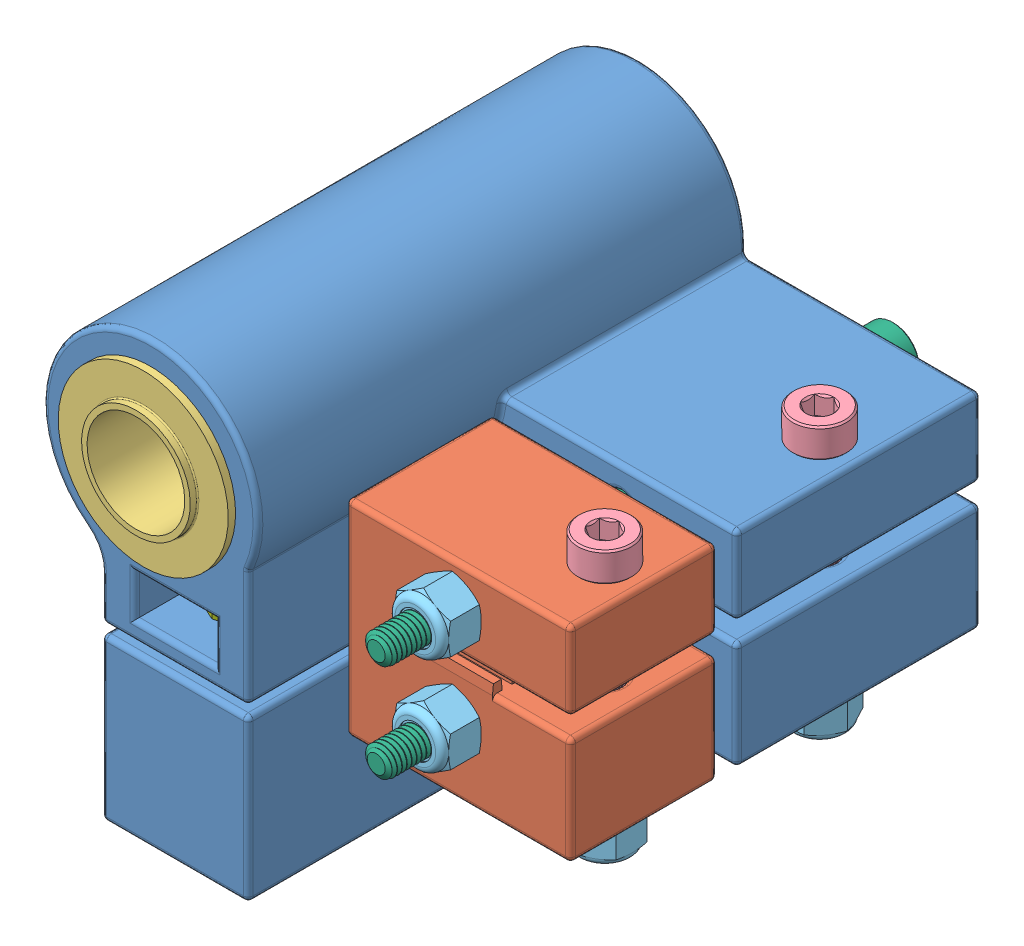
SolidWorks assembly XY_Axis_Belt_Tensioner_B, configuration Default. Lengths in mm.
Overall size (46.09 45 54.64).
14 component instances, 8 part files, 28 mates.
Components (placement in the parent):
- XY Axis Belt Tensioner B-1: XY Axis Belt Tensioner B [Default] at origin size (46 45 50)
- XY Axis Belt Tensioner Block B-1: XY Axis Belt Tensioner Block B [Default] at (0 1 -55.5) size (23 21 15.06)
- a_7z41mpsb10m-1: a_7z41mpsb10m [Default] at (5 34 -24.25) x (1 0 0) z (0 1 0) size (17.4 11.55 17.4)
- a_7z41mpsb10m-2: a_7z41mpsb10m [Default] at (5 34 -75.75) x (1 0 0) z (0 -1 0) size (17.4 11.55 17.4)
- 3mmX25mm_Sockethead(McMaster_91290A125)-1: 3mmX25mm_Sockethead(McMaster_91290A125) [91290A125] at (36 8 -40.5) x (1 0 0) z (0 -1 0) size (5.5 5.5 28.26)
- 3mmX25mm_Sockethead(McMaster_91290A125)-2: 3mmX25mm_Sockethead(McMaster_91290A125) [91290A125] at (36 8 -62.5) x (1 0 0) z (0 -1 0) size (5.5 5.5 28.26)
- 3mm_Hex_Nylock_Nut(McMaster_90576A102)-1: 3mm_Hex_Nylock_Nut(McMaster_90576A102) [90576A102] at (36 12 -40.5) x (1 0 0) z (0 0 -1) size (5.5 4.1 6.35)
- 3mm_Hex_Nylock_Nut(McMaster_90576A102)-2: 3mm_Hex_Nylock_Nut(McMaster_90576A102) [90576A102] at (36 12 -62.5) x (0.810201 0 0.586153) z (0.586153 0 -0.810201) size (5.5 4.1 6.35)
- 3mm_Hex_Nylock_Nut(McMaster_90576A102)-3: 3mm_Hex_Nylock_Nut(McMaster_90576A102) [90576A102] at (28.1 19 -33) x (1 0 0) z (0 -1 0) size (5.5 4.1 6.35)
- 3mm_Hex_Nylock_Nut(McMaster_90576A102)-4: 3mm_Hex_Nylock_Nut(McMaster_90576A102) [90576A102] at (28.1 29 -33) x (1 0 0) z (0 -1 0) size (5.5 4.1 6.35)
- 3mmX50mm_Sockethead(McMaster_91290A137)-1: 3mmX50mm_Sockethead(McMaster_91290A137) [91290A137] at (28.1 29 -25) size (5.5 5.5 53.26)
- 3mmX50mm_Sockethead(McMaster_91290A137)-2: 3mmX50mm_Sockethead(McMaster_91290A137) [91290A137] at (28.1 19 -25) size (5.5 5.5 53.26)
- 5mm_Hex_Nut(McMaster_90591A146)-1: 5mm_Hex_Nut(McMaster_90591A146) [90591A146] at (7.5 21.375 -33.4) x (0.5 0 -0.866025) z (0.866025 0 0.5) size (8 4.31 9.24)
- 5mmX16mm_Buttonhead(McMaster_91239A232)-1: 5mmX16mm_Buttonhead(McMaster_91239A232) [91239A232] at (7.5 3.25 -33.4) x (1 0 0) z (0 -1 0) size (9.5 9.5 19.24)
Mates (geometry in assembly coordinates):
- Concentric1: concentric anti-aligned: cylinder of XY Axis Belt Tensioner B-1 through (5 34 -36) axis (0 0 1) radius 7.95; circle of a_7z41mpsb10m-1
- Coincident1: coincident anti-aligned: plane of XY Axis Belt Tensioner B-1 through (-4 22 -25) normal (0 0 1); plane of a_7z41mpsb10m-1 through (5 34 -25) normal (0 0 -1)
- Concentric2: concentric anti-aligned: cylinder of XY Axis Belt Tensioner B-1 through (5 34 -64) axis (0 0 -1) radius 7.95; circle of a_7z41mpsb10m-2
- Coincident2: coincident anti-aligned: plane of XY Axis Belt Tensioner B-1 through (-4 22 -75) normal (0 0 -1); plane of a_7z41mpsb10m-2 through (5 34 -75) normal (0 0 1)
- Concentric7: concentric aligned: cylinder of XY Axis Belt Tensioner B-1 through (28.1 29 -75) axis (0 0 1) radius 1.6; cylinder of XY Axis Belt Tensioner Block B-1 through (28.1 29 -48) axis (0 0 1) radius 1.6
- Concentric8: concentric aligned: cylinder of XY Axis Belt Tensioner B-1 through (28.1 19 -75) axis (0 0 1) radius 1.6; cylinder of XY Axis Belt Tensioner Block B-1 through (28.1 19 -48) axis (0 0 1) radius 1.6
- Distance1: distance = 2 mm anti-aligned: plane of XY Axis Belt Tensioner B-1 through (0 0 -50) normal (0 0 1); plane of XY Axis Belt Tensioner Block B-1 through (0 1 -48) normal (0 0 -1)
- Parallel1: parallel aligned: plane of XY Axis Belt Tensioner B-1 through (3.375 19.375 -39.9) normal (1 0 0); plane of 5mm_Hex_Nut(McMaster_90591A146)-1 through (11.5 23.375 -31.0906) normal (1 0 0)
- Coincident4: coincident anti-aligned: plane of XY Axis Belt Tensioner B-1 through (11.625 19.375 -39.9) normal (0 1 0); plane of 5mm_Hex_Nut(McMaster_90591A146)-1 through (-0.5 19.375 -33.4) normal (0 -1 0)
- Concentric9: concentric aligned: cylinder of XY Axis Belt Tensioner B-1 through (7.5 25 -33.4) axis (0 -1 0) radius 2.6; circle of 5mm_Hex_Nut(McMaster_90591A146)-1
- Concentric10: concentric aligned: cylinder of XY Axis Belt Tensioner B-1 through (7.5 25 -33.4) axis (0 -1 0) radius 2.6; cylinder of 5mmX16mm_Buttonhead(McMaster_91239A232)-1 through (7.5 3.25 -33.4) axis (0 -1 0) radius 4.75
- Coincident5: coincident anti-aligned: plane of XY Axis Belt Tensioner B-1 through (7.5 6 -33.4) normal (0 -1 0); plane of 5mmX16mm_Buttonhead(McMaster_91239A232)-1 through (7.5 6 -38.15) normal (0 1 0)
- Concentric11: concentric aligned: cylinder of XY Axis Belt Tensioner B-1 through (28.1 29 -75) axis (0 0 1) radius 1.6; cylinder of 3mmX50mm_Sockethead(McMaster_91290A137)-1 through (28.1 29 -75) axis (0 0 1) radius 1.5
- Concentric12: concentric aligned: cylinder of XY Axis Belt Tensioner B-1 through (28.1 19 -75) axis (0 0 1) radius 1.6; cylinder of 3mmX50mm_Sockethead(McMaster_91290A137)-2 through (28.1 19 -75) axis (0 0 1) radius 1.5
- Coincident6: coincident anti-aligned: plane of XY Axis Belt Tensioner B-1 through (-4 22 -75) normal (0 0 -1); plane of 3mmX50mm_Sockethead(McMaster_91290A137)-1 through (28.1 29 -75) normal (0 0 1)
- Coincident7: coincident anti-aligned: plane of XY Axis Belt Tensioner B-1 through (-4 22 -75) normal (0 0 -1); plane of 3mmX50mm_Sockethead(McMaster_91290A137)-2 through (28.1 19 -75) normal (0 0 1)
- Concentric13: concentric anti-aligned: cylinder of 3mm_Hex_Nylock_Nut(McMaster_90576A102)-4 through (28.1 29 -29.5905) axis (0 0 -1) radius 1.269; cylinder of 3mmX50mm_Sockethead(McMaster_91290A137)-1 through (28.1 29 -75) axis (0 0 1) radius 1.5
- Coincident8: coincident anti-aligned: plane of XY Axis Belt Tensioner Block B-1 through (0 1 -33) normal (0 0 1); plane of 3mm_Hex_Nylock_Nut(McMaster_90576A102)-4 through (28.1 32.1754 -33) normal (0 0 -1)
- Concentric14: concentric anti-aligned: cylinder of 3mm_Hex_Nylock_Nut(McMaster_90576A102)-3 through (28.1 19 -29.5905) axis (0 0 -1) radius 1.269; cylinder of 3mmX50mm_Sockethead(McMaster_91290A137)-2 through (28.1 19 -75) axis (0 0 1) radius 1.5
- Coincident9: coincident anti-aligned: plane of XY Axis Belt Tensioner Block B-1 through (0 1 -33) normal (0 0 1); plane of 3mm_Hex_Nylock_Nut(McMaster_90576A102)-3 through (28.1 22.1754 -33) normal (0 0 -1)
- Concentric15: concentric anti-aligned: cylinder of 3mmX25mm_Sockethead(McMaster_91290A125)-1 through (36 33 -40.5) axis (0 -1 0) radius 1.5; cylinder of 3mm_Hex_Nylock_Nut(McMaster_90576A102)-1 through (36 8.5905 -40.5) axis (0 1 0) radius 1.269
- Concentric16: concentric anti-aligned: cylinder of 3mmX25mm_Sockethead(McMaster_91290A125)-2 through (36 33 -62.5) axis (0 -1 0) radius 1.5; cylinder of 3mm_Hex_Nylock_Nut(McMaster_90576A102)-2 through (36 8.5905 -62.5) axis (0 1 0) radius 1.269
- Concentric17: concentric anti-aligned: cylinder of XY Axis Belt Tensioner Block B-1 through (36 7.4745 -40.5) axis (0 1 0) radius 1.6; cylinder of 3mmX25mm_Sockethead(McMaster_91290A125)-1 through (36 33 -40.5) axis (0 -1 0) radius 1.5
- Coincident10: coincident anti-aligned: plane of XY Axis Belt Tensioner Block B-1 through (17 12 -48) normal (0 -1 0); plane of 3mm_Hex_Nylock_Nut(McMaster_90576A102)-1 through (36 12 -37.3246) normal (0 1 0)
- Coincident11: coincident anti-aligned: plane of XY Axis Belt Tensioner Block B-1 through (40 33 -48) normal (0 1 0); plane of 3mmX25mm_Sockethead(McMaster_91290A125)-1 through (36 33 -40.5) normal (0 -1 0)
- Concentric18: concentric anti-aligned: cylinder of XY Axis Belt Tensioner B-1 through (36 7.4745 -62.5) axis (0 1 0) radius 1.6; cylinder of 3mmX25mm_Sockethead(McMaster_91290A125)-2 through (36 33 -62.5) axis (0 -1 0) radius 1.5
- Coincident12: coincident anti-aligned: plane of XY Axis Belt Tensioner B-1 through (40 33 -75) normal (0 1 0); plane of 3mmX25mm_Sockethead(McMaster_91290A125)-2 through (36 33 -62.5) normal (0 -1 0)
- Coincident13: coincident anti-aligned: plane of XY Axis Belt Tensioner B-1 through (23 12 -75) normal (0 -1 0); plane of 3mm_Hex_Nylock_Nut(McMaster_90576A102)-2 through (34.1387 12 -59.9273) normal (0 1 0)
